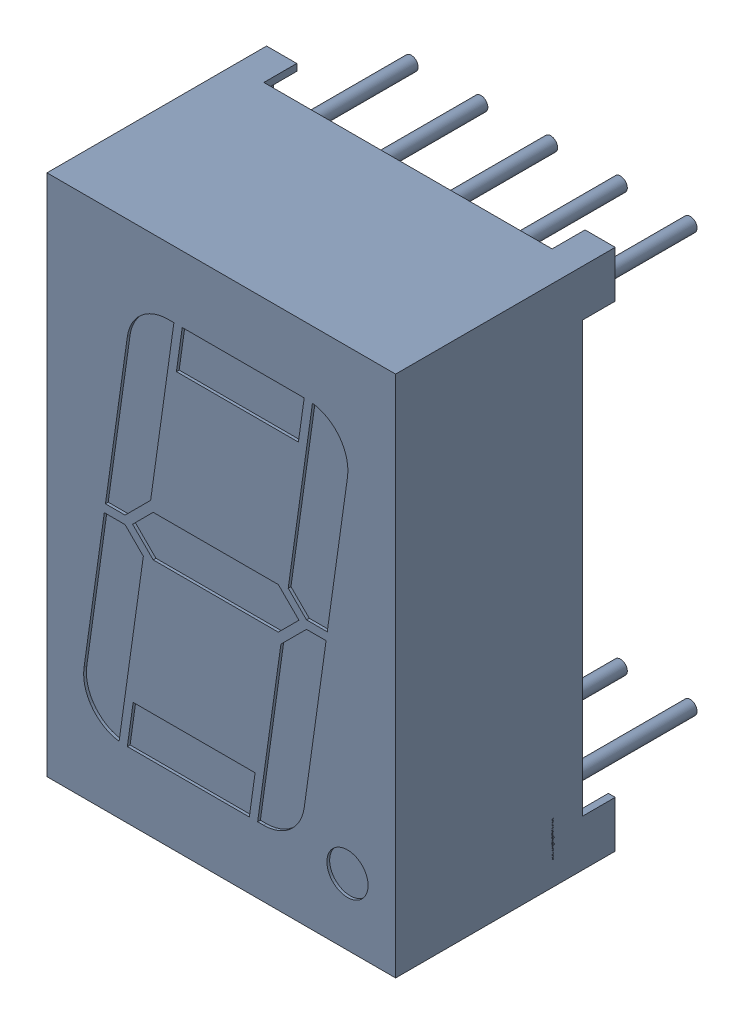
SolidWorks assembly SW3dPS-Disp_SA56-11, configuration Default. Lengths in mm.
Overall size (12.7 19.05 12).
2 component instances, 1 part files, 0 mates.
Components (placement in the parent):
- SW3dPS-Disp_SA56-11_Open_CASCADE_STEP_translator_6.2_78.2-1: SW3dPS-Disp_SA56-11_Open_CASCADE_STEP_translator_6.2_78.2 [Default] at origin size (12.7 19.05 12)
  - SW3dPS-Disp_SA56-11_Disp_SA56-12_2-1: SW3dPS-Disp_SA56-11_Disp_SA56-12_2 [Default] at (5.0801 7.6201 8.0327) x (1 0 0) z (0 -1 0) size (12.7 12 19.05)
